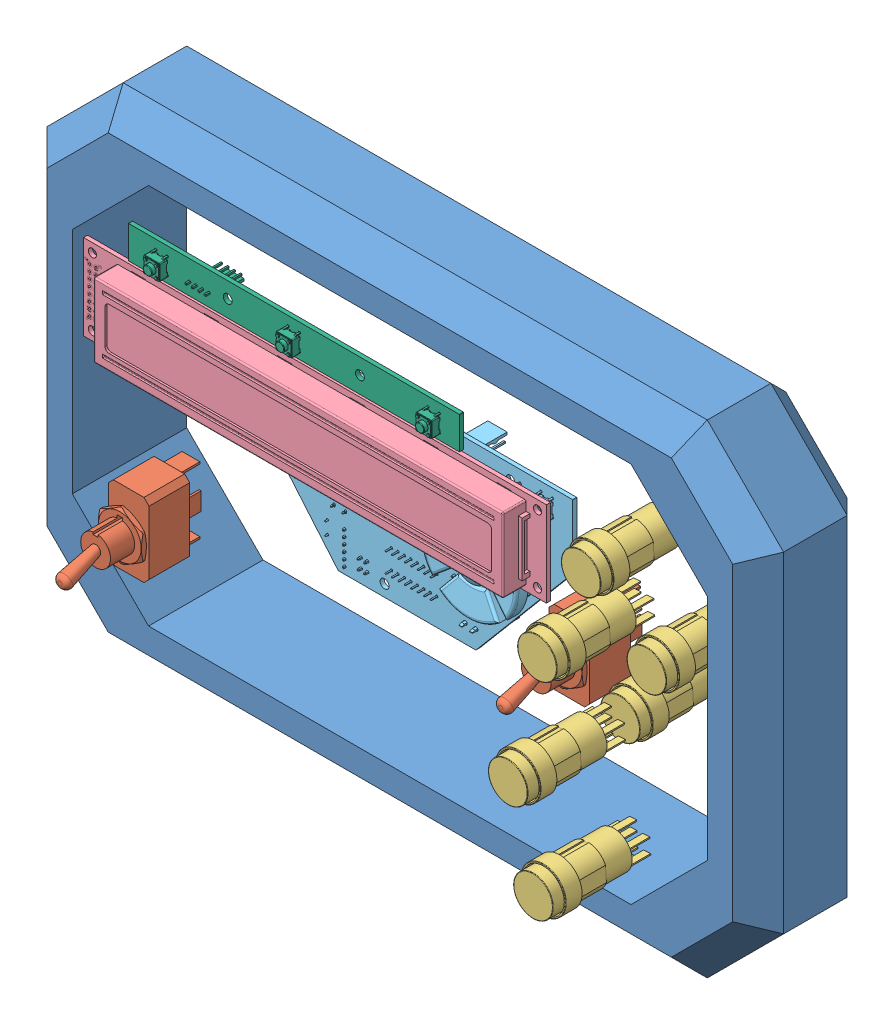
SolidWorks assembly Montagem3, configuration Valor predeterminado. Lengths in mm.
Overall size (289.68 190 110.08).
13 component instances, 6 part files, 1 mates.
Components (placement in the parent):
- 6 - TEC001 Moldura-1: 6 - TEC001 Moldura [Valor predeterminado] at (-29.9891 3.3334 -22.5) size (289.68 190 45)
- BCV3 112 103 - Controle chave geral-1: BCV3 112 103 - Controle chave geral [Default] at (-130.3947 -41.0254 16.7542) size (17 29 51.5)
- BCV3 112 102 - Controle botão-1: BCV3 112 102 - Controle botão [Valor predeterminado] at (70.9542 11.2273 12.1) x (0.998135 0.061049 0) z (0.061049 -0.998135 0) size (17.7 39.7 17.7)
- LCD Display 4002-1: LCD Display 4002 [Valor predeterminado] at (-59.3706 31.1219 17.9878) size (182 33.5 13.65)
- PCB_IHM-1: PCB_IHM [Valor predeterminado] at (-94.4407 -59.6429 -21.7574) size (130.25 70.25 27.35)
- PCB_IHM_Teclas_Superiores-1: PCB_IHM_Teclas_Superiores [Valor predeterminado] at (-127.2493 54.2789 27.91) size (130.25 12.75 19.2)
- BCV3 112 103 - Controle chave geral-2: BCV3 112 103 - Controle chave geral [Default] at (-4.2151 -43.8395 -30.3287) size (17 29 51.5)
- BCV3 112 102 - Controle botão-2: BCV3 112 102 - Controle botão [Valor predeterminado] at (43.5802 9.6556 27.75) x (0.998135 0.061049 0) z (0.061049 -0.998135 0) size (17.7 39.7 17.7)
- BCV3 112 102 - Controle botão-3: BCV3 112 102 - Controle botão [Valor predeterminado] at (57.6699 -56.7036 43.4) x (0.998135 0.061049 0) z (0.061049 -0.998135 0) size (17.7 39.7 17.7)
- BCV3 112 102 - Controle botão-4: BCV3 112 102 - Controle botão [Valor predeterminado] at (35.4545 -35.5999 -13.05) x (0.998135 0.061049 0) z (0.061049 -0.998135 0) size (17.7 39.7 17.7)
- BCV3 112 102 - Controle botão-5: BCV3 112 102 - Controle botão [Valor predeterminado] at (77.6402 -33.4182 -13.05) x (0.998135 0.061049 0) z (0.061049 -0.998135 0) size (17.7 39.7 17.7)
- BCV3 112 102 - Controle botão-6: BCV3 112 102 - Controle botão [Valor predeterminado] at (57.2016 -13.3907 52.85) x (0.998135 0.061049 0) z (0.061049 -0.998135 0) size (17.7 39.7 17.7)
- BCV3 112 102 - Controle botão-7: BCV3 112 102 - Controle botão [Valor predeterminado] at (64.9961 51.3206 31.95) x (0.998135 0.061049 0) z (0.061049 -0.998135 0) size (17.7 39.7 17.7)
Mates (geometry in assembly coordinates):
- Coincidente1: coincident aligned: plane of 6 - TEC001 Moldura-1 through (-29.9891 3.3334 22.5) normal (0 0 1); plane of BCV3 112 102 - Controle botão-1 through (70.9542 11.2273 22.5) normal (0 0 1)
